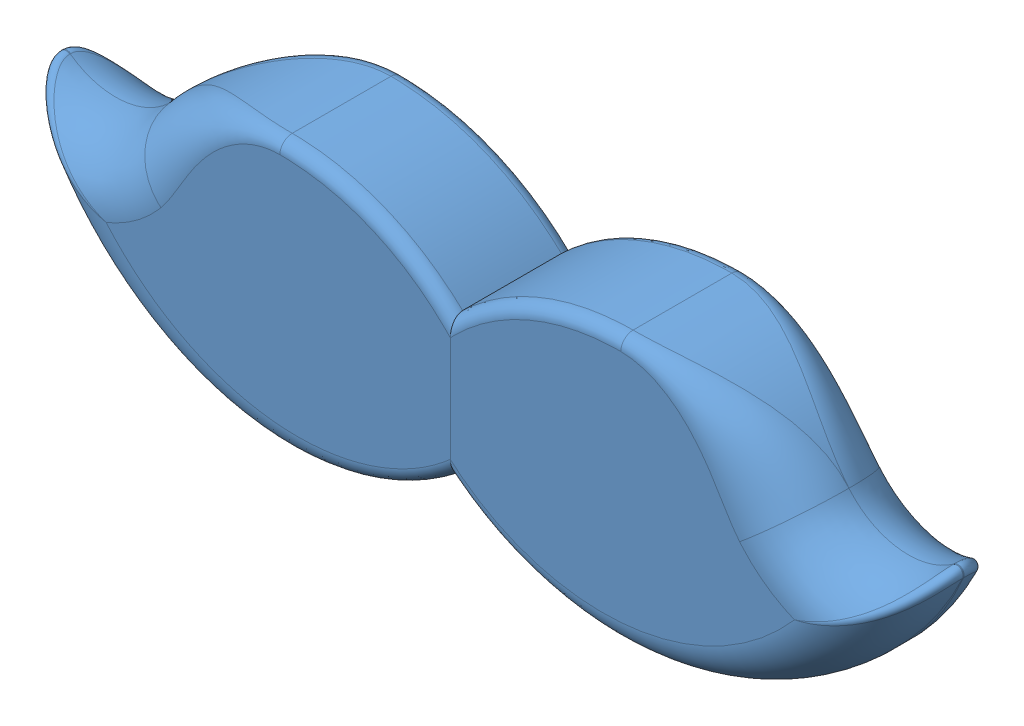
SolidWorks assembly trophy, configuration Default. Lengths in mm.
Overall size (297.77 88.22 45.29).
4 component instances, 3 part files, 9 mates.
Components (placement in the parent):
- stache-1: stache [left] at origin size (152.31 88.22 45.29)
- light_sheet-1: light_sheet [Default] at (0 10.7603 -18.5) x (-1 0 0) z (0 0 -1) size (185.97 50.6 1.5)
- teensy_holder-1: teensy_holder [Default] at (0 18.1603 -3.9) size (30.4 9.2 34.75)
- stache-4: stache [right] at origin size (152.31 88.22 45.29)
Mates (geometry in assembly coordinates):
- Width1: width anti-aligned: plane of teensy_holder-1 through (-11.2 20.1603 -19.5) normal (-1 0 0); plane of teensy_holder-1 through (11.2 20.1603 13.7) normal (1 0 0); plane of light_sheet-1 through (-11.4 17.9603 -18.499) normal (1 0 0); plane of light_sheet-1 through (11.4 17.9603 -18.499) normal (-1 0 0)
- Width2: width anti-aligned: plane of light_sheet-1 through (-11.4 17.9603 -18.499) normal (0 1 0); plane of light_sheet-1 through (-11.4 23.5603 -18.499) normal (0 -1 0); plane of teensy_holder-1 through (0 18.1603 -3.9) normal (0 -1 0); plane of teensy_holder-1 through (0 23.3603 -3.9) normal (0 1 0)
- Coincident9: coordinate: point of ?
- Coincident10: coincident aligned: plane of teensy_holder-1 through (0 18.1603 -3.9) normal (1 0 0); plane of assembly through (0 0 0) normal (1 0 0)
- Coincident11: coordinate: unknown of ?
- Coincident12: coincident anti-aligned: plane of light_sheet-1 through (0 10.7603 -18.5) normal (0 0 1); plane of teensy_holder-1 through (0 18.1603 -18.5) normal (0 0 -1)
- Coincident14: coincident anti-aligned: plane of light_sheet-1 through (0 10.7603 -18.5) normal (-1 0 0); plane of assembly through (0 0 0) normal (1 0 0)
- Coincident15: coincident aligned: plane of stache-1 through (-59.5425 74.0249 -20) normal (0 0 -1); plane of light_sheet-1 through (0 10.7603 -20) normal (0 0 -1)
- Width5: width aligned: plane of light_sheet-1 through (-25.1072 47.8133 -20) normal (0 1 0); plane of light_sheet-1 through (-89.8343 -0.3867 -20) normal (0 -1 0); plane of stache-1 through (-20 -0.7867 -19.1) normal (0 1 0); plane of stache-1 through (-65 48.2133 -19.1) normal (0 -1 0)
